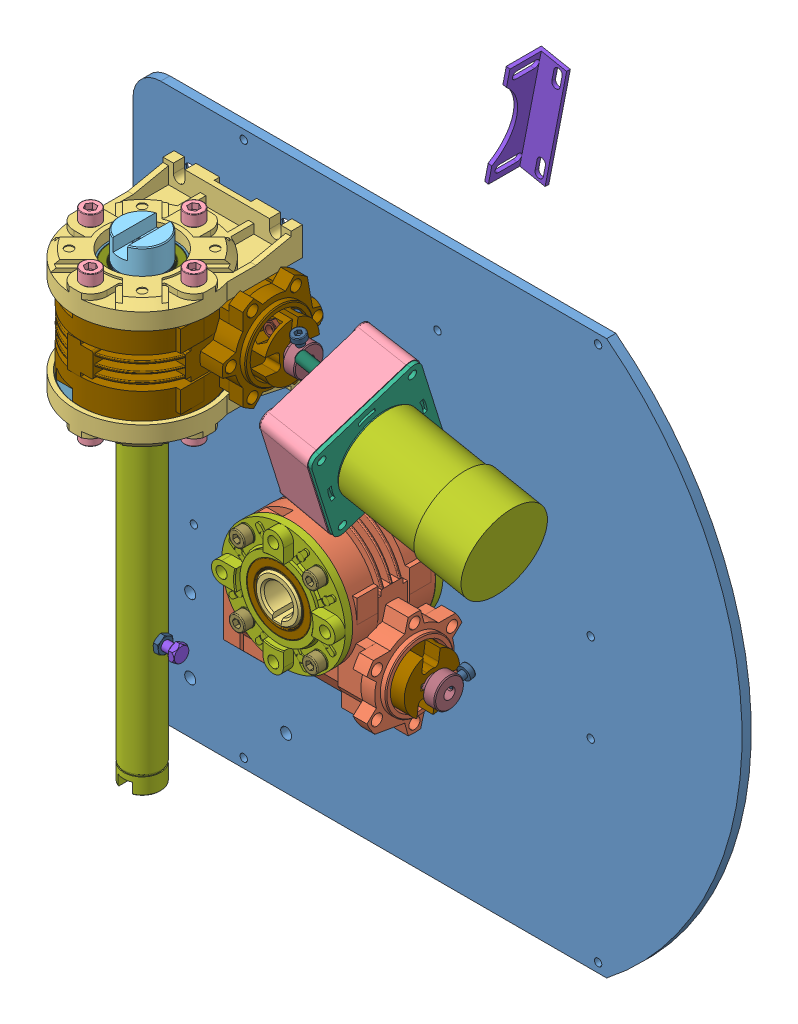
SolidWorks assembly Ensemble, configuration Défaut. Lengths in mm.
Overall size (330 419.62 100.08).
236 component instances, 64 part files, 7 mates.
Components (placement in the parent):
- Plaque tournante-1: Plaque tournante [Défaut] at (-24.2107 36.3062 -2.5) size (330 300 5)
- Réducteur1-28-1: Réducteur1-28 [Défaut] at (1.5972 -31.7943 34.5) x (-1 0 0) z (0 0 1) size (103.99 88.5 64.2)
  - Corps-1: Corps [Défaut] at (25.8079 -68.1005 0) size (87.5 88.5 51.49)
  - Arbre roue-1: Arbre roue [Défaut] at (25.8079 -68.1005 -6.1) x (-0.999923 0.012436 0) z (0 0 1) size (46.74 46.68 60)
  - Arbre vis-1: Arbre vis [Défaut] at (-7.6921 -41.1005 0) x (1 0 0) z (0 -0.163099 0.98661) size (73.2 23.6 23.6)
  - anneau ext20-1: anneau ext20 [Défaut] at (8.5079 -41.1005 0) x (0 -0.220515 0.975383) z (-1 0 0) size (22.7 24.65 1.2)
  - anneauext8-1: anneauext8 [Défaut] at (46.8079 -41.1005 0) x (0 0.220515 -0.975383) z (1 0 0) size (12.15 14.13 1)
  - couvercle-1: couvercle [Défaut] at (25.8079 -68.1005 29) x (0 0 -1) z (1 0 0) size (12 67 67)
  - couvercle-2: couvercle [Défaut] at (25.8079 -68.1005 -29) x (0 0 1) z (-1 0 0) size (12 67 67)
  - clinquant 47-1: clinquant 47 [Défaut] at (25.8079 -68.1005 19.9) size (47 47 0.1)
  - clinquant 47-2: clinquant 47 [Défaut] at (25.8079 -68.1005 -20.2) size (47 47 0.1)
  - JointSKF 25-35-1: JointSKF 25-35 [Défaut] at (25.8079 -68.1005 29) x (0 0 -1) z (0.997511 -0.070517 0) size (6.35 35 35)
  - JointSKF 25-35-2: JointSKF 25-35 [Défaut] at (25.8079 -68.1005 -29) x (0 0 1) z (-0.998272 -0.058768 0) size (6.35 35 35)
  - Bouchon-1: Bouchon [Défaut] at (59.8079 -41.1005 0) x (0 0.282701 -0.959208) z (1 0 0) size (30 30 6)
  - VisChc 5-10-1: VisChc 5-10 [Défaut] at (5.9906 -48.3198 -27.1) size (8.5 8.5 15)
  - VisChc 5-10-2: VisChc 5-10 [Défaut] at (6.0272 -87.9178 -27.1) x (0 1 0) z (0 0 1) size (8.5 8.5 15)
  - VisChc 5-10-3: VisChc 5-10 [Défaut] at (45.6252 -87.8812 -27.1) x (-1 0 0) z (0 0 1) size (8.5 8.5 15)
  - VisChc 5-10-4: VisChc 5-10 [Défaut] at (45.5886 -48.2833 -27.1) x (0 -1 0) z (0 0 1) size (8.5 8.5 15)
  - SymétrieVisChc 5-10-1: SymétrieVisChc 5-10 [Défaut] at (5.9906 -48.3198 27.1) size (8.5 8.5 15)
  - SymétrieVisChc 5-10-2: SymétrieVisChc 5-10 [Défaut] at (6.0272 -87.9178 27.1) x (0 1 0) z (0 0 1) size (8.5 8.5 15)
  - SymétrieVisChc 5-10-3: SymétrieVisChc 5-10 [Défaut] at (45.6252 -87.8812 27.1) x (-1 0 0) z (0 0 1) size (8.5 8.5 15)
  - SymétrieVisChc 5-10-4: SymétrieVisChc 5-10 [Défaut] at (45.5886 -48.2833 27.1) x (0 -1 0) z (0 0 1) size (8.5 8.5 15)
  - Vis bouchon M10-1: Vis bouchon M10 [Défaut] at (37.3524 -31.1005 -17) x (-0.01117 -0.999938 0) z (0.999938 -0.01117 0) size (10 10 10)
  - Roulement 20-32-1: Roulement 20-32 [Défaut] at (-0.6921 -41.1005 0) x (1 0 0) z (0 -0.6992 -0.714926) size (7 32 32)
    - Roulement Bint20-32-1: Roulement Bint20-32 [Défaut] at origin size (7 23.6 23.6)
    - Roulement Bext20-32-1: Roulement Bext20-32 [Défaut] at origin size (7 32 32)
    - Roulement billes 20-32-1: Roulement billes 20-32 [Défaut] at (0.3 0 -10.3) size (3.6 3.6 3.6)
    - Roulement billes 20-32-2: Roulement billes 20-32 [Défaut] at (0.3 3.5228 -9.6788) x (1 0 0) z (0 -0.34202 0.939693) size (3.6 3.6 3.6)
    - Roulement billes 20-32-3: Roulement billes 20-32 [Défaut] at (0.3 6.6207 -7.8903) x (1 0 0) z (0 -0.642788 0.766044) size (3.6 3.6 3.6)
    - Roulement billes 20-32-4: Roulement billes 20-32 [Défaut] at (0.3 8.9201 -5.15) x (1 0 0) z (0 -0.866025 0.5) size (3.6 3.6 3.6)
    - Roulement billes 20-32-5: Roulement billes 20-32 [Défaut] at (0.3 10.1435 -1.7886) x (1 0 0) z (0 -0.984808 0.173648) size (3.6 3.6 3.6)
    - Roulement billes 20-32-6: Roulement billes 20-32 [Défaut] at (0.3 10.1435 1.7886) x (1 0 0) z (0 -0.984808 -0.173648) size (3.6 3.6 3.6)
    - Roulement billes 20-32-7: Roulement billes 20-32 [Défaut] at (0.3 8.9201 5.15) x (1 0 0) z (0 -0.866025 -0.5) size (3.6 3.6 3.6)
    - Roulement billes 20-32-8: Roulement billes 20-32 [Défaut] at (0.3 6.6207 7.8903) x (1 0 0) z (0 -0.642788 -0.766044) size (3.6 3.6 3.6)
    - Roulement billes 20-32-9: Roulement billes 20-32 [Défaut] at (0.3 3.5228 9.6788) x (1 0 0) z (0 -0.34202 -0.939693) size (3.6 3.6 3.6)
    - Roulement billes 20-32-10: Roulement billes 20-32 [Défaut] at (0.3 0 10.3) x (1 0 0) z (0 0 -1) size (3.6 3.6 3.6)
    - Roulement billes 20-32-11: Roulement billes 20-32 [Défaut] at (0.3 -3.5228 9.6788) x (1 0 0) z (0 0.34202 -0.939693) size (3.6 3.6 3.6)
    - Roulement billes 20-32-12: Roulement billes 20-32 [Défaut] at (0.3 -6.6207 7.8903) x (1 0 0) z (0 0.642788 -0.766044) size (3.6 3.6 3.6)
    - Roulement billes 20-32-13: Roulement billes 20-32 [Défaut] at (0.3 -8.9201 5.15) x (1 0 0) z (0 0.866025 -0.5) size (3.6 3.6 3.6)
    - Roulement billes 20-32-14: Roulement billes 20-32 [Défaut] at (0.3 -10.1435 1.7886) x (1 0 0) z (0 0.984808 -0.173648) size (3.6 3.6 3.6)
    - Roulement billes 20-32-15: Roulement billes 20-32 [Défaut] at (0.3 -10.1435 -1.7886) x (1 0 0) z (0 0.984808 0.173648) size (3.6 3.6 3.6)
    - Roulement billes 20-32-16: Roulement billes 20-32 [Défaut] at (0.3 -8.9201 -5.15) x (1 0 0) z (0 0.866025 0.5) size (3.6 3.6 3.6)
    - Roulement billes 20-32-17: Roulement billes 20-32 [Défaut] at (0.3 -6.6207 -7.8903) x (1 0 0) z (0 0.642788 0.766044) size (3.6 3.6 3.6)
    - Roulement billes 20-32-18: Roulement billes 20-32 [Défaut] at (0.3 -3.5228 -9.6788) x (1 0 0) z (0 0.34202 0.939693) size (3.6 3.6 3.6)
  - Roulement10-30-1: Roulement10-30 [Défaut] at (47.8079 -41.1005 0) x (1 0 0) z (0 -0.820382 -0.571815) size (9 30 30)
    - Roulement bin10-30-1: Roulement bin10-30 [Défaut] at origin size (9 16 16)
    - Roulement Bext10-30-1: Roulement Bext10-30 [Défaut] at origin size (9 30 30)
    - Roulementbilles 10-30-1: Roulementbilles 10-30 [Défaut] at (0.6 0 -5.6) size (6 6 6)
    - Roulementbilles 10-30-2: Roulementbilles 10-30 [Défaut] at (0.6 3.9598 -3.9598) x (1 0 0) z (0 -0.707107 0.707107) size (6 6 6)
    - Roulementbilles 10-30-3: Roulementbilles 10-30 [Défaut] at (0.6 5.6 0) x (1 0 0) z (0 -1 0) size (6 6 6)
    - Roulementbilles 10-30-4: Roulementbilles 10-30 [Défaut] at (0.6 3.9598 3.9598) x (1 0 0) z (0 -0.707107 -0.707107) size (6 6 6)
    - Roulementbilles 10-30-5: Roulementbilles 10-30 [Défaut] at (0.6 0 5.6) x (1 0 0) z (0 0 -1) size (6 6 6)
    - Roulementbilles 10-30-6: Roulementbilles 10-30 [Défaut] at (0.6 -3.9598 3.9598) x (1 0 0) z (0 0.707107 -0.707107) size (6 6 6)
    - Roulementbilles 10-30-7: Roulementbilles 10-30 [Défaut] at (0.6 -5.6 0) x (1 0 0) z (0 1 0) size (6 6 6)
    - Roulementbilles 10-30-8: Roulementbilles 10-30 [Défaut] at (0.6 -3.9598 -3.9598) x (1 0 0) z (0 0.707107 0.707107) size (6 6 6)
  - Roulement 25-47-1: Roulement 25-47 [Défaut] at (25.8079 -68.1005 19.9) x (0 0 -1) z (0.950333 0.311235 0) size (8 47 47)
    - Roulement b int 25-47-1: Roulement b int 25-47 [Défaut] at origin size (8 31.6 31.6)
    - Roulement Bext 25-47-1: Roulement Bext 25-47 [Défaut] at origin size (8 47 47)
    - Roulement billes 25-47-1: Roulement billes 25-47 [Défaut] at (0.3 0 -12.8) size (6.6 6.6 6.6)
    - Roulement billes 25-47-2: Roulement billes 25-47 [Défaut] at (0.3 5.5537 -11.5324) x (1 0 0) z (0 -0.433884 0.900969) size (6.6 6.6 6.6)
    - Roulement billes 25-47-3: Roulement billes 25-47 [Défaut] at (0.3 10.0074 -7.9807) x (1 0 0) z (0 -0.781831 0.62349) size (6.6 6.6 6.6)
    - Roulement billes 25-47-4: Roulement billes 25-47 [Défaut] at (0.3 12.4791 -2.8483) x (1 0 0) z (0 -0.974928 0.222521) size (6.6 6.6 6.6)
    - Roulement billes 25-47-5: Roulement billes 25-47 [Défaut] at (0.3 12.4791 2.8483) x (1 0 0) z (0 -0.974928 -0.222521) size (6.6 6.6 6.6)
    - Roulement billes 25-47-6: Roulement billes 25-47 [Défaut] at (0.3 10.0074 7.9807) x (1 0 0) z (0 -0.781831 -0.62349) size (6.6 6.6 6.6)
    - Roulement billes 25-47-7: Roulement billes 25-47 [Défaut] at (0.3 5.5537 11.5324) x (1 0 0) z (0 -0.433884 -0.900969) size (6.6 6.6 6.6)
    - Roulement billes 25-47-8: Roulement billes 25-47 [Défaut] at (0.3 0 12.8) x (1 0 0) z (0 0 -1) size (6.6 6.6 6.6)
    - Roulement billes 25-47-9: Roulement billes 25-47 [Défaut] at (0.3 -5.5537 11.5324) x (1 0 0) z (0 0.433884 -0.900969) size (6.6 6.6 6.6)
    - Roulement billes 25-47-10: Roulement billes 25-47 [Défaut] at (0.3 -10.0074 7.9807) x (1 0 0) z (0 0.781831 -0.62349) size (6.6 6.6 6.6)
    - Roulement billes 25-47-11: Roulement billes 25-47 [Défaut] at (0.3 -12.4791 2.8483) x (1 0 0) z (0 0.974928 -0.222521) size (6.6 6.6 6.6)
    - Roulement billes 25-47-12: Roulement billes 25-47 [Défaut] at (0.3 -12.4791 -2.8483) x (1 0 0) z (0 0.974928 0.222521) size (6.6 6.6 6.6)
    - Roulement billes 25-47-13: Roulement billes 25-47 [Défaut] at (0.3 -10.0074 -7.9807) x (1 0 0) z (0 0.781831 0.62349) size (6.6 6.6 6.6)
    - Roulement billes 25-47-14: Roulement billes 25-47 [Défaut] at (0.3 -5.5537 -11.5324) x (1 0 0) z (0 0.433884 0.900969) size (6.6 6.6 6.6)
  - Roulement 25-47-2: Roulement 25-47 [Défaut] at (25.8079 -68.1005 -12.1) x (0 0 -1) z (-0.990262 -0.139215 0) size (8 47 47)
    - Roulement b int 25-47-1: Roulement b int 25-47 [Défaut] at origin size (8 31.6 31.6)
    - Roulement Bext 25-47-1: Roulement Bext 25-47 [Défaut] at origin size (8 47 47)
    - Roulement billes 25-47-1: Roulement billes 25-47 [Défaut] at (0.3 0 -12.8) size (6.6 6.6 6.6)
    - Roulement billes 25-47-2: Roulement billes 25-47 [Défaut] at (0.3 5.5537 -11.5324) x (1 0 0) z (0 -0.433884 0.900969) size (6.6 6.6 6.6)
    - Roulement billes 25-47-3: Roulement billes 25-47 [Défaut] at (0.3 10.0074 -7.9807) x (1 0 0) z (0 -0.781831 0.62349) size (6.6 6.6 6.6)
    - Roulement billes 25-47-4: Roulement billes 25-47 [Défaut] at (0.3 12.4791 -2.8483) x (1 0 0) z (0 -0.974928 0.222521) size (6.6 6.6 6.6)
    - Roulement billes 25-47-5: Roulement billes 25-47 [Défaut] at (0.3 12.4791 2.8483) x (1 0 0) z (0 -0.974928 -0.222521) size (6.6 6.6 6.6)
    - Roulement billes 25-47-6: Roulement billes 25-47 [Défaut] at (0.3 10.0074 7.9807) x (1 0 0) z (0 -0.781831 -0.62349) size (6.6 6.6 6.6)
    - Roulement billes 25-47-7: Roulement billes 25-47 [Défaut] at (0.3 5.5537 11.5324) x (1 0 0) z (0 -0.433884 -0.900969) size (6.6 6.6 6.6)
    - Roulement billes 25-47-8: Roulement billes 25-47 [Défaut] at (0.3 0 12.8) x (1 0 0) z (0 0 -1) size (6.6 6.6 6.6)
    - Roulement billes 25-47-9: Roulement billes 25-47 [Défaut] at (0.3 -5.5537 11.5324) x (1 0 0) z (0 0.433884 -0.900969) size (6.6 6.6 6.6)
    - Roulement billes 25-47-10: Roulement billes 25-47 [Défaut] at (0.3 -10.0074 7.9807) x (1 0 0) z (0 0.781831 -0.62349) size (6.6 6.6 6.6)
    - Roulement billes 25-47-11: Roulement billes 25-47 [Défaut] at (0.3 -12.4791 2.8483) x (1 0 0) z (0 0.974928 -0.222521) size (6.6 6.6 6.6)
    - Roulement billes 25-47-12: Roulement billes 25-47 [Défaut] at (0.3 -12.4791 -2.8483) x (1 0 0) z (0 0.974928 0.222521) size (6.6 6.6 6.6)
    - Roulement billes 25-47-13: Roulement billes 25-47 [Défaut] at (0.3 -10.0074 -7.9807) x (1 0 0) z (0 0.781831 0.62349) size (6.6 6.6 6.6)
    - Roulement billes 25-47-14: Roulement billes 25-47 [Défaut] at (0.3 -5.5537 -11.5324) x (1 0 0) z (0 0.433884 0.900969) size (6.6 6.6 6.6)
  - Circlips int roult-1: Circlips int roult [Défaut] at (-2.0921 -41.1005 0) x (0 -0.476355 -0.879253) z (1 0 0) size (32.02 32.54 1.2)
  - JointSKF 32-1: JointSKF 32 [Défaut] at (-6.6921 -41.1005 0) size (4 32 32)
  - anneau int 32-1: anneau int 32 [Défaut] at (-6.6921 -41.6003 -0.0145) x (0 -0.028995 0.99958) z (-1 0 0) size (33 32.22 1.2)
  - Accouplement-1: Accouplement [Défaut] at (-16.1921 -41.1005 0) x (0 0.287227 -0.957863) z (1 0 0) size (30 30 9)
  - plateau accouplement-1: plateau accouplement [Défaut] at (-9.1921 -41.1005 0) x (0 0.991528 0.129894) z (-1 0 0) size (30 29.92 19)
  - VisChcM4-16-1: VisChcM4-16 [Défaut] at (-22.6921 -34.8537 -9.1913) x (0.604562 0.103468 -0.789809) z (0 -0.991528 -0.129894) size (7 7 11)
  - Ecrou HM4-1: Ecrou HM4 [Défaut] at (-22.6921 -47.7436 -10.8799) x (-1 0 0) z (0 -0.991528 -0.129894) size (7 8.08 3)
  - Clavette accouplement-1: Clavette accouplement [Défaut] at (-19.1921 -41.5552 3.4703) x (1 0 0) z (0 -0.129894 0.991528) size (9.99 2.61 2.5)
  - arbre intermédiaire-1: arbre intermédiaire [Défaut] at (-7.6811 -41.1005 0) x (0 0.977328 -0.211732) z (-1 0 0) size (16 16 30)
  - VisChcM4-16-2: VisChcM4-16 [Défaut] at (-34.6811 -43.4296 -10.7506) x (1 0 0) z (0 0.211732 0.977328) size (7 7 11)
- Moto-réducteur-1: Moto-réducteur [Défaut] at (11.8617 144.6334 49.0848) x (0.07689 0.394605 -0.915628) z (-0.98154 0.191256 0) size (62.84 62.84 123.1)
  - Plaque support-1: Plaque support [Défaut] at (-13.2347 12.4995 -8.5) size (54 54 20)
  - Arbre de sortie 52dents-1: Arbre de sortie 52dents [Défaut] at (-3.2347 12.4995 2.5) size (27 27 49.6)
  - Arbre inter 50-13-1: Arbre inter 50-13 [Défaut] at (-15.1225 1.4205 2) x (-0.796237 0.604985 0) z (0 0 -1) size (25.98 26 22.9)
  - Arbre entrée 10-50-1: Arbre entrée 10-50 [Défaut] at (-25.2347 12.4995 -3) size (20.78 20.8 22.5)
  - entretoise-1: entretoise [Défaut] at (-25.2347 12.4995 2.5) size (4.5 4.5 5)
  - Contreplaque-1: Contreplaque [Défaut] at (-13.2347 12.4995 9) size (54 54 3.5)
  - vis cblz m3-1: vis cblz m3 [Default] at (-30.7347 27.9995 10.5) x (0.474676 -0.88016 0) z (0 0 -1) size (5.6 5.6 8.36)
  - Joint torique-1: Joint torique [Défaut] at (-3.391 12.5657 7.6457) size (8.33 8.33 1.2)
  - vis cblz m3-2: vis cblz m3 [Default] at (-30.7347 -3.0005 10.5) x (0.474676 -0.88016 0) z (0 0 -1) size (5.6 5.6 8.36)
  - vis cblz m3-3: vis cblz m3 [Default] at (4.2653 27.9995 10.5) x (0.474676 -0.88016 0) z (0 0 -1) size (5.6 5.6 8.36)
  - vis cblz m3-4: vis cblz m3 [Default] at (4.2653 -3.0005 10.5) x (0.474676 -0.88016 0) z (0 0 -1) size (5.6 5.6 8.36)
  - Carter-1: Carter [Défaut] at (-13.2347 12.4995 -11.5) x (0 -1 0) z (0 0 1) size (61 61 31.5)
  - Coussinet arbre sortie-1: Coussinet arbre sortie [Défaut] at (-3.2347 12.4995 8) x (0 0 1) z (-0.972252 -0.233935 0) size (12 15 15)
  - Plaque moteur-1: Plaque moteur [Défaut] at (-13.2347 12.4995 -13.5) size (60 60 5)
  - Moteur-1: Moteur [Défaut] at (-13.2347 12.4995 -4) x (0.5 -0.866025 0) z (0 0 -1) size (46 46 79.5)
  - vis cblz m3-5: vis cblz m3 [Default] at (-13.2347 29.9995 -12.5) x (-0.999476 0.032382 0) z (0 0 -1) size (5.6 5.6 8.36)
  - vis cblz m3-6: vis cblz m3 [Default] at (-28.3902 3.7495 -12.5) x (0.474676 -0.88016 0) z (0 0 -1) size (5.6 5.6 8.36)
  - vis cblz m3-7: vis cblz m3 [Default] at (1.9207 3.7495 -12.5) x (0.474676 -0.88016 0) z (0 0 -1) size (5.6 5.6 8.36)
  - vis cblz m3-8: vis cblz m3 [Default] at (-1.3847 -8.0253 12.5) x (0.474676 -0.88016 0) z (0 0 -1) size (5.6 5.6 8.36)
  - vis cblz m3-9: vis cblz m3 [Default] at (-36.9347 12.4995 12.5) x (0.474676 -0.88016 0) z (0 0 -1) size (5.6 5.6 8.36)
  - vis cblz m3-10: vis cblz m3 [Default] at (-1.3847 33.0243 12.5) x (0.474676 -0.88016 0) z (0 0 -1) size (5.6 5.6 8.36)
- Equerre de fixation-1: Equerre de fixation [Défaut] at (57.0432 305.9222 2.5) x (-0.191256 -0.98154 0) z (-0.98154 0.191256 0) size (61 19 16)
- Réducteur équipé 1-56-1-1: Réducteur équipé 1-56-1 [Défaut] at (-81.4028 119.8062 -13.6005) x (-1 0 0) z (0 -1 0) size (103.99 91.5 259)
  - Corps-1-1: Corps-1 [Défaut] at (25.8079 -68.1005 0) size (87.5 88.5 51.49)
  - Arbre roue-1-1: Arbre roue-1 [Défaut] at (25.8079 -68.1005 -6.1) x (0 1 0) z (0 0 1) size (46.74 46.68 60)
  - Arbre vis-1-1: Arbre vis-1 [Défaut] at (-7.6921 -41.1005 0) x (1 0 0) z (0 -0.163099 0.98661) size (73.2 23.6 23.6)
  - anneau ext20-1-1: anneau ext20-1 [Défaut] at (8.5079 -41.1005 0) x (0 -0.220515 0.975383) z (-1 0 0) size (22.7 24.65 1.2)
  - anneauext8-1-1: anneauext8-1 [Défaut] at (46.8079 -41.1005 0) x (0 0.220515 -0.975383) z (1 0 0) size (12.15 14.13 1)
  - couvercle-1-1: couvercle-1 [Défaut] at (25.8079 -68.1005 29) x (0 0 -1) z (1 0 0) size (12 67 67)
  - couvercle-1-2: couvercle-1 [Défaut] at (25.8079 -68.1005 -29) x (0 0 1) z (-1 0 0) size (12 67 67)
  - clinquant 47-1-1: clinquant 47-1 [Défaut] at (25.8079 -68.1005 19.9) size (47 47 0.1)
  - clinquant 47-1-2: clinquant 47-1 [Défaut] at (25.8079 -68.1005 -20.2) size (47 47 0.1)
  - JointSKF 25-35-1-1: JointSKF 25-35-1 [Défaut] at (25.8079 -68.1005 29) x (0 0 -1) z (0.997511 -0.070517 0) size (6.35 35 35)
  - JointSKF 25-35-1-2: JointSKF 25-35-1 [Défaut] at (25.8079 -68.1005 -29) x (0 0 1) z (-0.998272 -0.058768 0) size (6.35 35 35)
  - Bouchon-1-1: Bouchon-1 [Défaut] at (59.8079 -41.1005 0) x (0 0.282701 -0.959208) z (1 0 0) size (30 30 6)
  - VisChc 5-10-1-1: VisChc 5-10-1 [Défaut] at (5.9906 -48.3198 -27.1) size (8.5 8.5 15)
  - VisChc 5-10-1-2: VisChc 5-10-1 [Défaut] at (6.0272 -87.9178 -27.1) x (0 1 0) z (0 0 1) size (8.5 8.5 15)
  - VisChc 5-10-1-3: VisChc 5-10-1 [Défaut] at (45.6252 -87.8812 -27.1) x (-1 0 0) z (0 0 1) size (8.5 8.5 15)
  - VisChc 5-10-1-4: VisChc 5-10-1 [Défaut] at (45.5886 -48.2833 -27.1) x (0 -1 0) z (0 0 1) size (8.5 8.5 15)
  - SymétrieVisChc 5-10-1-1: SymétrieVisChc 5-10-1 [Défaut] at (5.9906 -48.3198 27.1) size (8.5 8.5 15)
  - SymétrieVisChc 5-10-1-2: SymétrieVisChc 5-10-1 [Défaut] at (6.0272 -87.9178 27.1) x (0 1 0) z (0 0 1) size (8.5 8.5 15)
  - SymétrieVisChc 5-10-1-3: SymétrieVisChc 5-10-1 [Défaut] at (45.6252 -87.8812 27.1) x (-1 0 0) z (0 0 1) size (8.5 8.5 15)
  - SymétrieVisChc 5-10-1-4: SymétrieVisChc 5-10-1 [Défaut] at (45.5886 -48.2833 27.1) x (0 -1 0) z (0 0 1) size (8.5 8.5 15)
  - Vis bouchon M10-1-1: Vis bouchon M10-1 [Défaut] at (37.3524 -31.1005 -17) x (-0.01117 -0.999938 0) z (0.999938 -0.01117 0) size (10 10 10)
  - Roulement 20-32-1-1: Roulement 20-32-1 [Défaut] at (-0.6921 -41.1005 0) x (1 0 0) z (0 -0.6992 -0.714926) size (7 32 32)
    - Roulement Bint20-32-1: Roulement Bint20-32 [Défaut] at origin size (7 23.6 23.6)
    - Roulement Bext20-32-1: Roulement Bext20-32 [Défaut] at origin size (7 32 32)
    - Roulement billes 20-32-1: Roulement billes 20-32 [Défaut] at (0.3 0 -10.3) size (3.6 3.6 3.6)
    - Roulement billes 20-32-2: Roulement billes 20-32 [Défaut] at (0.3 3.5228 -9.6788) x (1 0 0) z (0 -0.34202 0.939693) size (3.6 3.6 3.6)
    - Roulement billes 20-32-3: Roulement billes 20-32 [Défaut] at (0.3 6.6207 -7.8903) x (1 0 0) z (0 -0.642788 0.766044) size (3.6 3.6 3.6)
    - Roulement billes 20-32-4: Roulement billes 20-32 [Défaut] at (0.3 8.9201 -5.15) x (1 0 0) z (0 -0.866025 0.5) size (3.6 3.6 3.6)
    - Roulement billes 20-32-5: Roulement billes 20-32 [Défaut] at (0.3 10.1435 -1.7886) x (1 0 0) z (0 -0.984808 0.173648) size (3.6 3.6 3.6)
    - Roulement billes 20-32-6: Roulement billes 20-32 [Défaut] at (0.3 10.1435 1.7886) x (1 0 0) z (0 -0.984808 -0.173648) size (3.6 3.6 3.6)
    - Roulement billes 20-32-7: Roulement billes 20-32 [Défaut] at (0.3 8.9201 5.15) x (1 0 0) z (0 -0.866025 -0.5) size (3.6 3.6 3.6)
    - Roulement billes 20-32-8: Roulement billes 20-32 [Défaut] at (0.3 6.6207 7.8903) x (1 0 0) z (0 -0.642788 -0.766044) size (3.6 3.6 3.6)
    - Roulement billes 20-32-9: Roulement billes 20-32 [Défaut] at (0.3 3.5228 9.6788) x (1 0 0) z (0 -0.34202 -0.939693) size (3.6 3.6 3.6)
    - Roulement billes 20-32-10: Roulement billes 20-32 [Défaut] at (0.3 0 10.3) x (1 0 0) z (0 0 -1) size (3.6 3.6 3.6)
    - Roulement billes 20-32-11: Roulement billes 20-32 [Défaut] at (0.3 -3.5228 9.6788) x (1 0 0) z (0 0.34202 -0.939693) size (3.6 3.6 3.6)
    - Roulement billes 20-32-12: Roulement billes 20-32 [Défaut] at (0.3 -6.6207 7.8903) x (1 0 0) z (0 0.642788 -0.766044) size (3.6 3.6 3.6)
    - Roulement billes 20-32-13: Roulement billes 20-32 [Défaut] at (0.3 -8.9201 5.15) x (1 0 0) z (0 0.866025 -0.5) size (3.6 3.6 3.6)
    - Roulement billes 20-32-14: Roulement billes 20-32 [Défaut] at (0.3 -10.1435 1.7886) x (1 0 0) z (0 0.984808 -0.173648) size (3.6 3.6 3.6)
    - Roulement billes 20-32-15: Roulement billes 20-32 [Défaut] at (0.3 -10.1435 -1.7886) x (1 0 0) z (0 0.984808 0.173648) size (3.6 3.6 3.6)
    - Roulement billes 20-32-16: Roulement billes 20-32 [Défaut] at (0.3 -8.9201 -5.15) x (1 0 0) z (0 0.866025 0.5) size (3.6 3.6 3.6)
    - Roulement billes 20-32-17: Roulement billes 20-32 [Défaut] at (0.3 -6.6207 -7.8903) x (1 0 0) z (0 0.642788 0.766044) size (3.6 3.6 3.6)
    - Roulement billes 20-32-18: Roulement billes 20-32 [Défaut] at (0.3 -3.5228 -9.6788) x (1 0 0) z (0 0.34202 0.939693) size (3.6 3.6 3.6)
  - Roulement10-30-1: Roulement10-30 [Défaut] at (47.8079 -41.1005 0) x (1 0 0) z (0 -0.820382 -0.571815) size (9 30 30)
    - Roulement bin10-30-1: Roulement bin10-30 [Défaut] at origin size (9 16 16)
    - Roulement Bext10-30-1: Roulement Bext10-30 [Défaut] at origin size (9 30 30)
    - Roulementbilles 10-30-1: Roulementbilles 10-30 [Défaut] at (0.6 0 -5.6) size (6 6 6)
    - Roulementbilles 10-30-2: Roulementbilles 10-30 [Défaut] at (0.6 3.9598 -3.9598) x (1 0 0) z (0 -0.707107 0.707107) size (6 6 6)
    - Roulementbilles 10-30-3: Roulementbilles 10-30 [Défaut] at (0.6 5.6 0) x (1 0 0) z (0 -1 0) size (6 6 6)
    - Roulementbilles 10-30-4: Roulementbilles 10-30 [Défaut] at (0.6 3.9598 3.9598) x (1 0 0) z (0 -0.707107 -0.707107) size (6 6 6)
    - Roulementbilles 10-30-5: Roulementbilles 10-30 [Défaut] at (0.6 0 5.6) x (1 0 0) z (0 0 -1) size (6 6 6)
    - Roulementbilles 10-30-6: Roulementbilles 10-30 [Défaut] at (0.6 -3.9598 3.9598) x (1 0 0) z (0 0.707107 -0.707107) size (6 6 6)
    - Roulementbilles 10-30-7: Roulementbilles 10-30 [Défaut] at (0.6 -5.6 0) x (1 0 0) z (0 1 0) size (6 6 6)
    - Roulementbilles 10-30-8: Roulementbilles 10-30 [Défaut] at (0.6 -3.9598 -3.9598) x (1 0 0) z (0 0.707107 0.707107) size (6 6 6)
  - Roulement 25-47-1: Roulement 25-47 [Défaut] at (25.8079 -68.1005 19.9) x (0 0 -1) z (0.950333 0.311235 0) size (8 47 47)
    - Roulement b int 25-47-1: Roulement b int 25-47 [Défaut] at origin size (8 31.6 31.6)
    - Roulement Bext 25-47-1: Roulement Bext 25-47 [Défaut] at origin size (8 47 47)
    - Roulement billes 25-47-1: Roulement billes 25-47 [Défaut] at (0.3 0 -12.8) size (6.6 6.6 6.6)
    - Roulement billes 25-47-2: Roulement billes 25-47 [Défaut] at (0.3 5.5537 -11.5324) x (1 0 0) z (0 -0.433884 0.900969) size (6.6 6.6 6.6)
    - Roulement billes 25-47-3: Roulement billes 25-47 [Défaut] at (0.3 10.0074 -7.9807) x (1 0 0) z (0 -0.781831 0.62349) size (6.6 6.6 6.6)
    - Roulement billes 25-47-4: Roulement billes 25-47 [Défaut] at (0.3 12.4791 -2.8483) x (1 0 0) z (0 -0.974928 0.222521) size (6.6 6.6 6.6)
    - Roulement billes 25-47-5: Roulement billes 25-47 [Défaut] at (0.3 12.4791 2.8483) x (1 0 0) z (0 -0.974928 -0.222521) size (6.6 6.6 6.6)
    - Roulement billes 25-47-6: Roulement billes 25-47 [Défaut] at (0.3 10.0074 7.9807) x (1 0 0) z (0 -0.781831 -0.62349) size (6.6 6.6 6.6)
    - Roulement billes 25-47-7: Roulement billes 25-47 [Défaut] at (0.3 5.5537 11.5324) x (1 0 0) z (0 -0.433884 -0.900969) size (6.6 6.6 6.6)
    - Roulement billes 25-47-8: Roulement billes 25-47 [Défaut] at (0.3 0 12.8) x (1 0 0) z (0 0 -1) size (6.6 6.6 6.6)
    - Roulement billes 25-47-9: Roulement billes 25-47 [Défaut] at (0.3 -5.5537 11.5324) x (1 0 0) z (0 0.433884 -0.900969) size (6.6 6.6 6.6)
    - Roulement billes 25-47-10: Roulement billes 25-47 [Défaut] at (0.3 -10.0074 7.9807) x (1 0 0) z (0 0.781831 -0.62349) size (6.6 6.6 6.6)
    - Roulement billes 25-47-11: Roulement billes 25-47 [Défaut] at (0.3 -12.4791 2.8483) x (1 0 0) z (0 0.974928 -0.222521) size (6.6 6.6 6.6)
    - Roulement billes 25-47-12: Roulement billes 25-47 [Défaut] at (0.3 -12.4791 -2.8483) x (1 0 0) z (0 0.974928 0.222521) size (6.6 6.6 6.6)
    - Roulement billes 25-47-13: Roulement billes 25-47 [Défaut] at (0.3 -10.0074 -7.9807) x (1 0 0) z (0 0.781831 0.62349) size (6.6 6.6 6.6)
    - Roulement billes 25-47-14: Roulement billes 25-47 [Défaut] at (0.3 -5.5537 -11.5324) x (1 0 0) z (0 0.433884 0.900969) size (6.6 6.6 6.6)
  - Roulement 25-47-2: Roulement 25-47 [Défaut] at (25.8079 -68.1005 -12.1) x (0 0 -1) z (0.190943 0.981601 0) size (8 47 47)
    - Roulement b int 25-47-1: Roulement b int 25-47 [Défaut] at origin size (8 31.6 31.6)
    - Roulement Bext 25-47-1: Roulement Bext 25-47 [Défaut] at origin size (8 47 47)
    - Roulement billes 25-47-1: Roulement billes 25-47 [Défaut] at (0.3 0 -12.8) size (6.6 6.6 6.6)
    - Roulement billes 25-47-2: Roulement billes 25-47 [Défaut] at (0.3 5.5537 -11.5324) x (1 0 0) z (0 -0.433884 0.900969) size (6.6 6.6 6.6)
    - Roulement billes 25-47-3: Roulement billes 25-47 [Défaut] at (0.3 10.0074 -7.9807) x (1 0 0) z (0 -0.781831 0.62349) size (6.6 6.6 6.6)
    - Roulement billes 25-47-4: Roulement billes 25-47 [Défaut] at (0.3 12.4791 -2.8483) x (1 0 0) z (0 -0.974928 0.222521) size (6.6 6.6 6.6)
    - Roulement billes 25-47-5: Roulement billes 25-47 [Défaut] at (0.3 12.4791 2.8483) x (1 0 0) z (0 -0.974928 -0.222521) size (6.6 6.6 6.6)
    - Roulement billes 25-47-6: Roulement billes 25-47 [Défaut] at (0.3 10.0074 7.9807) x (1 0 0) z (0 -0.781831 -0.62349) size (6.6 6.6 6.6)
    - Roulement billes 25-47-7: Roulement billes 25-47 [Défaut] at (0.3 5.5537 11.5324) x (1 0 0) z (0 -0.433884 -0.900969) size (6.6 6.6 6.6)
    - Roulement billes 25-47-8: Roulement billes 25-47 [Défaut] at (0.3 0 12.8) x (1 0 0) z (0 0 -1) size (6.6 6.6 6.6)
    - Roulement billes 25-47-9: Roulement billes 25-47 [Défaut] at (0.3 -5.5537 11.5324) x (1 0 0) z (0 0.433884 -0.900969) size (6.6 6.6 6.6)
    - Roulement billes 25-47-10: Roulement billes 25-47 [Défaut] at (0.3 -10.0074 7.9807) x (1 0 0) z (0 0.781831 -0.62349) size (6.6 6.6 6.6)
    - Roulement billes 25-47-11: Roulement billes 25-47 [Défaut] at (0.3 -12.4791 2.8483) x (1 0 0) z (0 0.974928 -0.222521) size (6.6 6.6 6.6)
    - Roulement billes 25-47-12: Roulement billes 25-47 [Défaut] at (0.3 -12.4791 -2.8483) x (1 0 0) z (0 0.974928 0.222521) size (6.6 6.6 6.6)
    - Roulement billes 25-47-13: Roulement billes 25-47 [Défaut] at (0.3 -10.0074 -7.9807) x (1 0 0) z (0 0.781831 0.62349) size (6.6 6.6 6.6)
    - Roulement billes 25-47-14: Roulement billes 25-47 [Défaut] at (0.3 -5.5537 -11.5324) x (1 0 0) z (0 0.433884 0.900969) size (6.6 6.6 6.6)
  - Circlips int roult-1: Circlips int roult [Défaut] at (-2.0921 -41.1005 0) x (0 -0.476355 -0.879253) z (1 0 0) size (32.02 32.54 1.2)
  - JointSKF 32-1: JointSKF 32 [Défaut] at (-6.6921 -41.1005 0) size (4 32 32)
  - anneau int 32-1: anneau int 32 [Défaut] at (-6.6921 -41.6003 -0.0145) x (0 -0.028995 0.99958) z (-1 0 0) size (33 32.22 1.2)
  - Accouplement-1: Accouplement [Défaut] at (-16.1921 -41.1005 0) x (0 0.287227 -0.957863) z (1 0 0) size (30 30 9)
  - plateau accouplement-1: plateau accouplement [Défaut] at (-9.1921 -41.1005 0) x (0 0.991528 0.129894) z (-1 0 0) size (30 29.92 19)
  - VisChcM4-16-1: VisChcM4-16 [Défaut] at (-22.6921 -34.8537 -9.1913) x (0.604562 0.103468 -0.789809) z (0 -0.991528 -0.129894) size (7 7 11)
  - Ecrou HM4-1: Ecrou HM4 [Défaut] at (-22.6921 -47.7436 -10.8799) x (-1 0 0) z (0 -0.991528 -0.129894) size (7 8.08 3)
  - Clavette accouplement-1: Clavette accouplement [Défaut] at (-19.1921 -41.5552 3.4703) x (1 0 0) z (0 -0.129894 0.991528) size (9.99 2.61 2.5)
  - arbre intermédiaire-1: arbre intermédiaire [Défaut] at (-7.6811 -41.1005 0) x (0 0.977328 -0.211732) z (-1 0 0) size (16 16 30)
  - VisChcM4-16-2: VisChcM4-16 [Défaut] at (-34.6811 -43.4296 -10.7506) x (1 0 0) z (0 0.211732 0.977328) size (7 7 11)
  - Patte de fixation-1-1: Patte de fixation-1 [Défaut] at (25.8079 -68.1005 35) x (1 0 0) z (0 0 -1) size (73 88.5 15.5)
  - Patte de fixation-1-2: Patte de fixation-1 [Défaut] at (25.8079 -68.1005 -35) x (-1 0 0) z (0 0 1) size (73 88.5 15.5)
  - Vis M6 10-1-1: Vis M6 10-1 [Default] at (25.8079 -96.1005 34.5) x (-0.997053 -0.076719 0) z (0 0 -1) size (10 10 16)
  - Vis M6 10-1-5: Vis M6 10-1 [Default] at (53.8079 -68.1005 -34.5) size (10 10 16)
  - Vis M6 10-1-6: Vis M6 10-1 [Default] at (25.8079 -40.1005 -34.5) x (0 1 0) z (0 0 1) size (10 10 16)
  - Vis M6 10-1-7: Vis M6 10-1 [Default] at (-2.1921 -68.1005 -34.5) x (-1 0 0) z (0 0 1) size (10 10 16)
  - Vis M6 10-1-8: Vis M6 10-1 [Default] at (25.8079 -96.1005 -34.5) x (0 -1 0) z (0 0 1) size (10 10 16)
  - Vis M6 10-1-2: Vis M6 10-1 [Default] at (53.8079 -68.1005 34.5) x (0.076719 -0.997053 0) z (0 0 -1) size (10 10 16)
  - Vis M6 10-1-3: Vis M6 10-1 [Default] at (25.8079 -40.1005 34.5) x (0.997053 0.076719 0) z (0 0 -1) size (10 10 16)
  - Vis M6 10-1-4: Vis M6 10-1 [Default] at (-2.1921 -68.1005 34.5) x (-0.076719 0.997053 0) z (0 0 -1) size (10 10 16)
  - Arbre entraineur-1-1: Arbre entraineur-1 [Défaut] at (25.8079 -68.1005 -44.1) x (0 1 0) z (0 0 1) size (25 25 92)
  - Clavette-1-1: Clavette-1 [Défaut] at (30.8079 -68.1005 14.9) x (0 0 -1) z (1 0 0) size (35.02 5 5)
  - Arbre panneau-1-1: Arbre panneau-1 [Défaut] at (25.8079 -68.1005 29.9) x (0 1 0) z (0 0 1) size (20 20 185)
  - vis H M5-20-1-1: vis H M5-20-1 [Défaut] at (7.6079 -68.1005 144.9) x (0 0.000249 1) z (-1 0 0) size (9.79 8 23.65)
  - goupille_elastique 5x36-1-1: goupille_elastique 5x36-1 [Défaut] at (43.1536 -68.1005 40.9) x (0 0.773663 -0.633597) z (-1 0 0) size (4.96 5 36)
  - Ecrou M5-1-1: Ecrou M5-1 [Défaut] at (15.8079 -68.1005 144.9) x (0 0.070718 0.997496) z (-1 0 0) size (9.24 8 2.71)
Mates (geometry in assembly coordinates):
- Coaxial3: concentric anti-aligned: cylinder of Plaque tournante-1; cylinder of Réducteur1-28-1/Arbre roue-1
- Coïncidente2: coincident anti-aligned: plane of Plaque tournante-1 through (-24.2107 36.3062 2.5) normal (0 0 1); plane of Réducteur1-28-1/couvercle-2 through (3.7893 36.3062 2.5) normal (0 0 -1)
- Coaxial4: concentric anti-aligned: cylinder of Plaque tournante-1; cylinder of Réducteur1-28-1/couvercle-1
- Coïncidente3: coincident anti-aligned: plane of Moto-réducteur-1/Plaque moteur-1 through (19.4502 112.9924 23.2364) normal (0.98154 -0.191256 0); plane of Equerre de fixation-1 through (45.3766 246.0482 2.5) normal (-0.98154 0.191256 0)
- Coïncidente5: coincident anti-aligned: plane of Plaque tournante-1 through (-24.2107 36.3062 2.5) normal (0 0 1); plane of Equerre de fixation-1 through (45.3766 246.0482 2.5) normal (0 0 -1)
- Coaxial8: concentric anti-aligned: cylinder of Plaque tournante-1; cylinder of Réducteur équipé 1-56-1-1/Patte de fixation-1-2
- Coaxial10: concentric anti-aligned: cylinder of Plaque tournante-1; cylinder of Réducteur équipé 1-56-1-1/Patte de fixation-1-2
